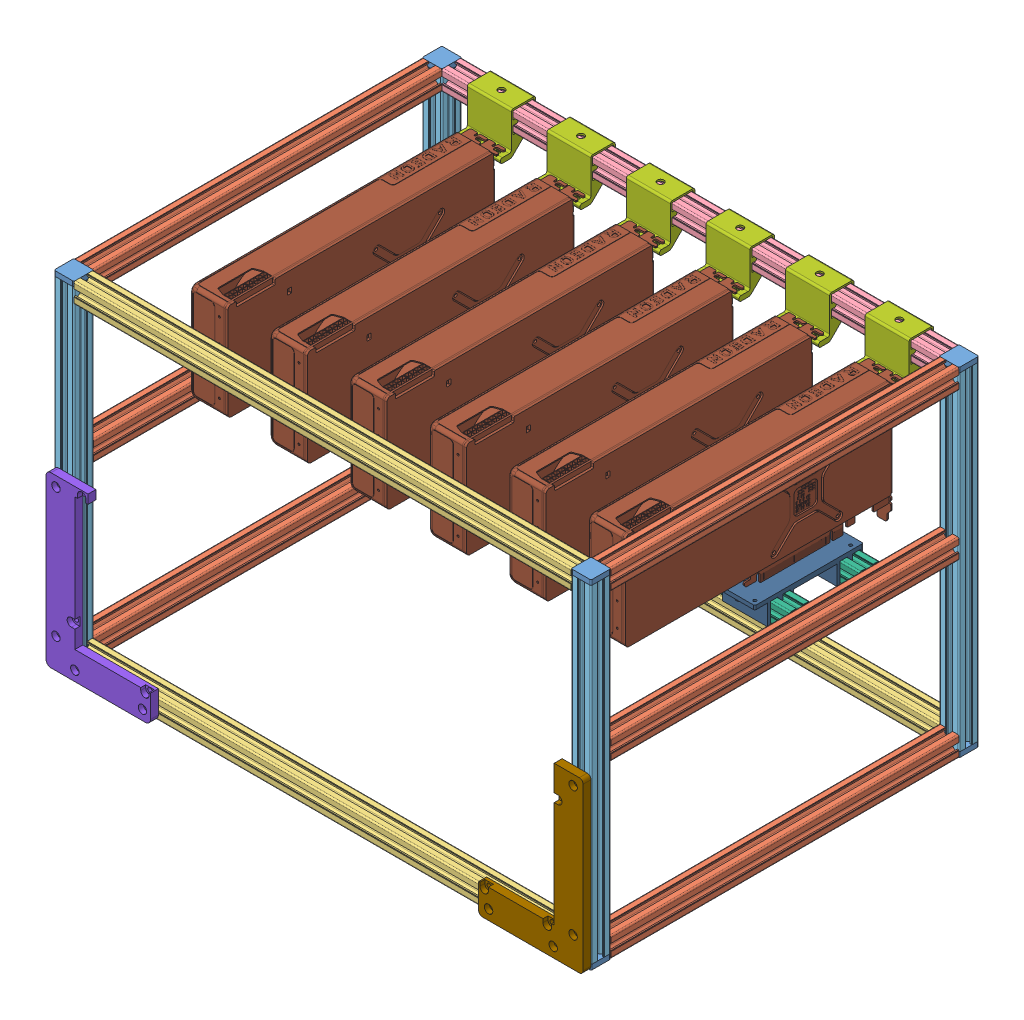
SolidWorks assembly Assem1, configuration Default. Lengths in mm.
Overall size (540 341.75 400.25).
50 component instances, 13 part files, 93 mates.
Components (placement in the parent):
- corner_joint-1: corner_joint [Default] at origin size (20 5 20)
- corner_joint-2: corner_joint [Default] at (520 335 -370) size (20 5 20)
- corner_joint-3: corner_joint [Default] at (520 335 0) size (20 5 20)
- corner_joint-4: corner_joint [Default] at (0 335 0) size (20 5 20)
- corner_joint-5: corner_joint [Default] at (0 335 -370) size (20 5 20)
- corner_joint-6: corner_joint [Default] at (520 0 0) size (20 5 20)
- corner_joint-7: corner_joint [Default] at (0 0 -370) size (20 5 20)
- corner_joint-8: corner_joint [Default] at (520 0 -370) size (20 5 20)
- AlumuniumProfile35-1: AlumuniumProfile35 [Default] at (0 182 -10) x (1 0 0) z (0 1 0) size (20 350 20)
- AlumuniumProfile35-2: AlumuniumProfile35 [Default] at (0 10 -360) x (1 0 0) z (0 -1 0) size (20 350 20)
- AlumuniumProfile35-3: AlumuniumProfile35 [Default] at (520 10 -10) x (1 0 0) z (0 1 0) size (20 350 20)
- AlumuniumProfile35-4: AlumuniumProfile35 [Default] at (0 330 -10) x (1 0 0) z (0 1 0) size (20 350 20)
- AlumuniumProfile35-5: AlumuniumProfile35 [Default] at (520 330 -10) x (1 0 0) z (0 1 0) size (20 350 20)
- AlumuniumProfile35-6: AlumuniumProfile35 [Default] at (520 182 -10) x (1 0 0) z (0 1 0) size (20 350 20)
- AlumuniumProfile35-7: AlumuniumProfile35 [Default] at (385.6516 -131.4751 125.2315) size (20 350 20) (hidden)
- AlumuniumProfile35-8: AlumuniumProfile35 [Default] at (633.6839 -115.6045 218.3051) size (20 350 20) (hidden)
- AlumuniumProfile35-9: AlumuniumProfile35 [Default] at (604.1368 -238.7208 188.5621) size (20 350 20) (hidden)
- AlumuniumProfile50-1: AlumuniumProfile50 [Default] at (10 330 0) x (0 -1 0) z (0 0 1) size (20 500 20)
- AlumuniumProfile50GPUBracket-1: AlumuniumProfile50GPUBracket [Default] at (510 330 -370) x (0 0 1) z (0 -1 0) size (20 500 20)
- AlumuniumProfile50-3: AlumuniumProfile50 [Default] at (510 10 -370) x (0 1 0) z (0 0 1) size (20 500 20)
- AlumuniumProfile33-5: AlumuniumProfile33 [Default] at (520 5 0) x (-1 0 0) z (0 0 -1) size (20 330 20)
- AlumuniumProfile33-6: AlumuniumProfile33 [Default] at (0 5 -370) size (20 330 20)
- AlumuniumProfile33-7: AlumuniumProfile33 [Default] at (0 5 0) size (20 330 20)
- AlumuniumProfile33-8: AlumuniumProfile33 [Default] at (520 5 -370) x (-1 0 0) z (0 0 -1) size (20 330 20)
- AlumuniumProfile50-5: AlumuniumProfile50 [Default] at (510 10 0) x (0 1 0) z (0 0 1) size (20 500 20)
- AlumuniumProfile50RiserBracket-4: AlumuniumProfile50RiserBracket [Default] at (510 182 -290) x (0 1 0) z (0 0 1) size (20 500 20)
- AlumuniumProfile50RiserBracket-1: AlumuniumProfile50RiserBracket [Default] at (10 182 -220) x (0 -1 0) z (0 0 1) size (20 500 20)
- GPURailBracket-5: GPURailBracket [Default] at (460.015 329.5 -370) x (1 0 0) z (0 1 0) size (44.23 35.5 42.25)
- PSUBracketRight-1: PSUBracketRight [Default] at (42.5 85 14) x (1 0 0) z (0 1 0) size (105 8 170)
- PSUBracketLeft-1: PSUBracketLeft [Default] at (477.5 85 14) x (1 0 0) z (0 1 0) size (105 8 170)
- RiserRail-1: RiserRail [Default] at (468.25 196 -248.5) x (-1 0 0) z (0 0 -1) size (45 24.5 109)
- vega 56 reference v2 v1.step-1: vega 56 reference v2 v1.step [Default] at (474.13 309.081 -356.75) x (0 0 1) z (0 -1 0) size (280 39 123.43)
- RiserRail-12: RiserRail [Default] at (388.25 196 -248.5) x (-1 0 0) z (0 0 -1) size (45 24.5 109)
- RiserRail-13: RiserRail [Default] at (308.25 196 -248.5) x (-1 0 0) z (0 0 -1) size (45 24.5 109)
- RiserRail-14: RiserRail [Default] at (228.25 196 -248.5) x (-1 0 0) z (0 0 -1) size (45 24.5 109)
- RiserRail-15: RiserRail [Default] at (148.25 196 -248.5) x (-1 0 0) z (0 0 -1) size (45 24.5 109)
- RiserRail-16: RiserRail [Default] at (68.25 196 -248.5) x (-1 0 0) z (0 0 -1) size (45 24.5 109)
- GPURailBracket-7: GPURailBracket [Default] at (380.015 329.5 -370) x (1 0 0) z (0 1 0) size (44.23 35.5 42.25)
- GPURailBracket-8: GPURailBracket [Default] at (300.015 329.5 -370) x (1 0 0) z (0 1 0) size (44.23 35.5 42.25)
- GPURailBracket-9: GPURailBracket [Default] at (220.015 329.5 -370) x (1 0 0) z (0 1 0) size (44.23 35.5 42.25)
- GPURailBracket-10: GPURailBracket [Default] at (140.015 329.5 -370) x (1 0 0) z (0 1 0) size (44.23 35.5 42.25)
- GPURailBracket-11: GPURailBracket [Default] at (60.015 329.5 -370) x (1 0 0) z (0 1 0) size (44.23 35.5 42.25)
- vega 56 reference v2 v1.step-7: vega 56 reference v2 v1.step [Default] at (394.13 309.081 -356.75) x (0 0 1) z (0 -1 0) size (280 39 123.43)
- vega 56 reference v2 v1.step-8: vega 56 reference v2 v1.step [Default] at (314.13 309.081 -356.75) x (0 0 1) z (0 -1 0) size (280 39 123.43)
- vega 56 reference v2 v1.step-9: vega 56 reference v2 v1.step [Default] at (234.13 309.081 -356.75) x (0 0 1) z (0 -1 0) size (280 39 123.43)
- vega 56 reference v2 v1.step-10: vega 56 reference v2 v1.step [Default] at (154.13 309.081 -356.75) x (0 0 1) z (0 -1 0) size (280 39 123.43)
- vega 56 reference v2 v1.step-11: vega 56 reference v2 v1.step [Default] at (74.13 309.081 -356.75) x (0 0 1) z (0 -1 0) size (280 39 123.43)
- GPUDrillingHelperExtender-1: GPUDrillingHelperExtender [Default] at (70 329.75 -370) x (0 0 -1) z (0 -1 0) size (26.5 80 23.5) (hidden)
- GPUDrillingHelperInit-1: GPUDrillingHelperInit [Default] at (10 329.75 -370) x (0 0 -1) z (0 -1 0) size (26.5 63 23.5) (hidden)
- GPUDrillingHelperExtender-2: GPUDrillingHelperExtender [Default] at (150 329.75 -370) x (0 0 -1) z (0 -1 0) size (26.5 80 23.5) (hidden)
Mates (geometry in assembly coordinates):
- Coincident36: coincident anti-aligned: plane of AlumuniumProfile33-7 through (0 5 0) normal (0 -1 0); plane of corner_joint-1 through (-8.5 5 -8.5) normal (0 1 0)
- Coincident37: coincident aligned: plane of AlumuniumProfile33-7 through (10 335 0) normal (1 0 0); plane of corner_joint-1 through (10 5 8.5) normal (1 0 0)
- Coincident38: coincident aligned: plane of AlumuniumProfile33-7 through (0 335 10) normal (0 0 1); plane of corner_joint-1 through (-8.5 5 10) normal (0 0 1)
- Coincident39: coincident anti-aligned: plane of AlumuniumProfile35-2 through (0 10 -10) normal (0 0 1); plane of corner_joint-1 through (-8.5 5 -10) normal (0 0 -1)
- Coincident40: coincident aligned: plane of AlumuniumProfile35-2 through (10 10 -10) normal (1 0 0); plane of corner_joint-1 through (10 5 8.5) normal (1 0 0)
- Coincident41: coincident aligned: plane of AlumuniumProfile35-2 through (0 0 -10) normal (0 -1 0); plane of corner_joint-1 through (-8.5 0 -8.5) normal (0 -1 0)
- Coincident42: coincident anti-aligned: plane of AlumuniumProfile50-5 through (10 10 0) normal (-1 0 0); plane of corner_joint-1 through (10 5 8.5) normal (1 0 0)
- Coincident43: coincident aligned: plane of AlumuniumProfile50-5 through (10 10 10) normal (0 0 1); plane of corner_joint-1 through (-8.5 5 10) normal (0 0 1)
- Coincident44: coincident aligned: plane of AlumuniumProfile50-5 through (10 0 0) normal (0 -1 0); plane of corner_joint-1 through (-8.5 0 -8.5) normal (0 -1 0)
- Coincident45: coincident aligned: plane of AlumuniumProfile33-5 through (520 335 0) normal (0 1 0); plane of AlumuniumProfile33-7 through (0 335 0) normal (0 1 0)
- Coincident46: coincident anti-aligned: plane of AlumuniumProfile33-5 through (510 335 0) normal (-1 0 0); plane of AlumuniumProfile50-5 through (510 10 0) normal (1 0 0)
- Coincident47: coincident aligned: plane of AlumuniumProfile33-5 through (520 335 10) normal (0 0 1); plane of AlumuniumProfile50-5 through (10 10 10) normal (0 0 1)
- Coincident48: coincident aligned: plane of AlumuniumProfile33-6 through (0 335 -370) normal (0 1 0); plane of AlumuniumProfile33-7 through (0 335 0) normal (0 1 0)
- Coincident49: coincident anti-aligned: plane of AlumuniumProfile35-2 through (0 10 -360) normal (0 0 -1); plane of AlumuniumProfile33-6 through (0 335 -360) normal (0 0 1)
- Coincident50: coincident aligned: plane of AlumuniumProfile35-2 through (-10 10 -10) normal (-1 0 0); plane of AlumuniumProfile33-6 through (-10 335 -370) normal (-1 0 0)
- Coincident51: coincident aligned: plane of AlumuniumProfile33-7 through (0 335 0) normal (0 1 0); plane of AlumuniumProfile33-8 through (520 335 -370) normal (0 1 0)
- Coincident52: coincident anti-aligned: plane of AlumuniumProfile33-8 through (510 335 -370) normal (-1 0 0); plane of AlumuniumProfile50-5 through (510 10 0) normal (1 0 0)
- Coincident53: coincident anti-aligned: plane of AlumuniumProfile35-2 through (0 10 -360) normal (0 0 -1); plane of AlumuniumProfile33-8 through (520 335 -360) normal (0 0 1)
- Coincident54: coincident anti-aligned: plane of AlumuniumProfile50-3 through (10 10 -370) normal (-1 0 0); plane of AlumuniumProfile33-6 through (10 335 -370) normal (1 0 0)
- Coincident55: coincident aligned: plane of AlumuniumProfile50-3 through (10 10 -360) normal (0 0 1); plane of AlumuniumProfile33-6 through (0 335 -360) normal (0 0 1)
- Coincident56: coincident aligned: plane of AlumuniumProfile35-2 through (0 0 -10) normal (0 -1 0); plane of AlumuniumProfile50-3 through (10 0 -370) normal (0 -1 0)
- Coincident57: coincident anti-aligned: plane of AlumuniumProfile50GPUBracket-1 through (10 330 -370) normal (-1 0 0); plane of AlumuniumProfile33-6 through (10 335 -370) normal (1 0 0)
- Coincident59: coincident anti-aligned: plane of AlumuniumProfile33-6 through (0 335 -370) normal (0 1 0); plane of corner_joint-5 through (-8.5 335 -378.5) normal (0 -1 0)
- Coincident60: coincident aligned: plane of AlumuniumProfile33-6 through (-10 335 -370) normal (-1 0 0); plane of corner_joint-5 through (-10 340 -361.5) normal (-1 0 0)
- Coincident61: coincident aligned: plane of AlumuniumProfile33-6 through (0 335 -360) normal (0 0 1); plane of corner_joint-5 through (-8.5 340 -360) normal (0 0 1)
- Coincident63: coincident anti-aligned: plane of AlumuniumProfile50-1 through (510 330 0) normal (1 0 0); plane of AlumuniumProfile33-5 through (510 335 0) normal (-1 0 0)
- Coincident64: coincident aligned: plane of AlumuniumProfile50-1 through (510 330 10) normal (0 0 1); plane of AlumuniumProfile33-5 through (520 335 10) normal (0 0 1)
- Coincident66: coincident anti-aligned: plane of AlumuniumProfile35-4 through (0 330 -360) normal (0 0 -1); plane of AlumuniumProfile33-6 through (0 335 -360) normal (0 0 1)
- Coincident67: coincident aligned: plane of AlumuniumProfile35-4 through (0 340 -360) normal (0 1 0); plane of corner_joint-5 through (-8.5 340 -378.5) normal (0 1 0)
- Coincident68: coincident aligned: plane of AlumuniumProfile35-4 through (-10 330 -360) normal (-1 0 0); plane of AlumuniumProfile33-6 through (-10 335 -370) normal (-1 0 0)
- Coincident69: coincident anti-aligned: plane of AlumuniumProfile33-8 through (520 335 -360) normal (0 0 1); plane of AlumuniumProfile35-5 through (520 330 -360) normal (0 0 -1)
- Coincident70: coincident aligned: plane of AlumuniumProfile33-8 through (510 335 -370) normal (-1 0 0); plane of AlumuniumProfile35-5 through (510 330 -360) normal (-1 0 0)
- Coincident72: coincident anti-aligned: plane of AlumuniumProfile35-3 through (520 10 -360) normal (0 0 -1); plane of AlumuniumProfile33-8 through (520 335 -360) normal (0 0 1)
- Coincident73: coincident aligned: plane of AlumuniumProfile35-3 through (510 10 -360) normal (-1 0 0); plane of AlumuniumProfile33-8 through (510 335 -370) normal (-1 0 0)
- Coincident74: coincident aligned: plane of AlumuniumProfile35-3 through (520 0 -360) normal (0 -1 0); plane of AlumuniumProfile50-3 through (10 0 -370) normal (0 -1 0)
- Coincident75: coincident aligned: plane of AlumuniumProfile33-7 through (-10 335 0) normal (-1 0 0); plane of corner_joint-4 through (-10 340 8.5) normal (-1 0 0)
- Coincident76: coincident aligned: plane of AlumuniumProfile33-7 through (0 335 10) normal (0 0 1); plane of corner_joint-4 through (-8.5 340 10) normal (0 0 1)
- Coincident77: coincident anti-aligned: plane of AlumuniumProfile33-7 through (0 335 0) normal (0 1 0); plane of corner_joint-4 through (-8.5 335 -8.5) normal (0 -1 0)
- Coincident78: coincident aligned: plane of AlumuniumProfile33-8 through (520 335 -360) normal (0 0 1); plane of corner_joint-2 through (511.5 340 -360) normal (0 0 1)
- Coincident79: coincident aligned: plane of AlumuniumProfile33-8 through (510 335 -370) normal (-1 0 0); plane of corner_joint-2 through (510 340 -361.5) normal (-1 0 0)
- Coincident80: coincident anti-aligned: plane of AlumuniumProfile33-8 through (520 335 -370) normal (0 1 0); plane of corner_joint-2 through (511.5 335 -378.5) normal (0 -1 0)
- Coincident81: coincident aligned: plane of AlumuniumProfile33-5 through (520 335 10) normal (0 0 1); plane of corner_joint-3 through (511.5 340 10) normal (0 0 1)
- Coincident82: coincident aligned: plane of AlumuniumProfile33-5 through (510 335 0) normal (-1 0 0); plane of corner_joint-3 through (510 340 8.5) normal (-1 0 0)
- Coincident83: coincident anti-aligned: plane of AlumuniumProfile33-5 through (520 335 0) normal (0 1 0); plane of corner_joint-3 through (511.5 335 -8.5) normal (0 -1 0)
- Coincident85: coincident aligned: plane of AlumuniumProfile50-5 through (10 10 10) normal (0 0 1); plane of corner_joint-6 through (511.5 5 10) normal (0 0 1)
- Coincident86: coincident aligned: plane of AlumuniumProfile33-5 through (510 335 0) normal (-1 0 0); plane of corner_joint-6 through (510 5 8.5) normal (-1 0 0)
- Coincident87: coincident aligned: plane of AlumuniumProfile50-5 through (10 0 0) normal (0 -1 0); plane of corner_joint-6 through (511.5 0 -8.5) normal (0 -1 0)
- Coincident88: coincident aligned: plane of AlumuniumProfile33-8 through (520 335 -360) normal (0 0 1); plane of corner_joint-8 through (511.5 5 -360) normal (0 0 1)
- Coincident92: coincident aligned: plane of AlumuniumProfile35-3 through (520 0 -360) normal (0 -1 0); plane of corner_joint-8 through (511.5 0 -378.5) normal (0 -1 0)
- Coincident93: coincident aligned: plane of AlumuniumProfile33-8 through (530 335 -370) normal (1 0 0); plane of corner_joint-8 through (530 5 -361.5) normal (1 0 0)
- Coincident94: coincident aligned: plane of AlumuniumProfile33-6 through (0 335 -380) normal (0 0 -1); plane of corner_joint-7 through (-8.5 5 -380) normal (0 0 -1)
- Coincident95: coincident aligned: plane of AlumuniumProfile50-3 through (10 0 -370) normal (0 -1 0); plane of corner_joint-7 through (-8.5 0 -378.5) normal (0 -1 0)
- Coincident96: coincident aligned: plane of AlumuniumProfile33-6 through (-10 335 -370) normal (-1 0 0); plane of corner_joint-7 through (-10 5 -361.5) normal (-1 0 0)
- Coincident100: coincident anti-aligned: plane of AlumuniumProfile35-1 through (0 182 -360) normal (0 0 -1); plane of AlumuniumProfile33-6 through (0 335 -360) normal (0 0 1)
- Coincident101: coincident aligned: plane of AlumuniumProfile35-1 through (-10 182 -360) normal (-1 0 0); plane of AlumuniumProfile33-6 through (-10 335 -370) normal (-1 0 0)
- Distance3: distance = 148 mm aligned: plane of AlumuniumProfile35-1 through (0 192 -360) normal (0 1 0); plane of corner_joint-5 through (-8.5 340 -378.5) normal (0 1 0)
- Coincident103: coincident anti-aligned: plane of AlumuniumProfile33-8 through (520 335 -360) normal (0 0 1); plane of AlumuniumProfile35-6 through (520 182 -360) normal (0 0 -1)
- Coincident104: coincident aligned: plane of AlumuniumProfile33-8 through (510 335 -370) normal (-1 0 0); plane of AlumuniumProfile35-6 through (510 182 -360) normal (-1 0 0)
- Coincident105: coincident aligned: plane of AlumuniumProfile35-1 through (0 192 -360) normal (0 1 0); plane of AlumuniumProfile35-6 through (520 192 -360) normal (0 1 0)
- Coincident106: coincident anti-aligned: plane of AlumuniumProfile50-4 through (510 182 -290) normal (1 0 0); plane of AlumuniumProfile35-6 through (510 182 -360) normal (-1 0 0)
- Coincident109: coincident anti-aligned: plane of AlumuniumProfile50-6 through (510 181.8711 -220) normal (1 0 0); plane of AlumuniumProfile35-6 through (510 182 -360) normal (-1 0 0)
- Coincident130: coincident anti-aligned: plane of AlumuniumProfile33-7 through (0 335 10) normal (0 0 1); plane of PSUBracketRight-1 through (42.5 85 10) normal (0 0 -1)
- Coincident131: coincident aligned: plane of AlumuniumProfile33-7 through (-10 335 0) normal (-1 0 0); plane of PSUBracketRight-1 through (-10 85 18) normal (-1 0 0)
- Coincident132: coincident aligned: plane of AlumuniumProfile50-5 through (10 0 0) normal (0 -1 0); plane of PSUBracketRight-1 through (42.5 0 18) normal (0 -1 0)
- Coincident133: coincident anti-aligned: plane of AlumuniumProfile33-5 through (520 335 10) normal (0 0 1); plane of PSUBracketLeft-1 through (477.5 85 10) normal (0 0 -1)
- Coincident134: coincident aligned: plane of AlumuniumProfile33-5 through (530 335 0) normal (1 0 0); plane of PSUBracketLeft-1 through (530 85 18) normal (1 0 0)
- Coincident135: coincident aligned: plane of AlumuniumProfile50-5 through (10 0 0) normal (0 -1 0); plane of PSUBracketLeft-1 through (477.5 0 18) normal (0 -1 0)
- Coincident150: coincident aligned: plane of AlumuniumProfile50GPUBracket-1 through (10 340 -370) normal (0 1 0); plane of corner_joint-2 through (511.5 340 -378.5) normal (0 1 0)
- Coincident151: coincident aligned: plane of AlumuniumProfile50GPUBracket-1 through (10 330 -380) normal (0 0 -1); plane of AlumuniumProfile33-8 through (520 335 -380) normal (0 0 -1)
- Coincident152: coincident aligned: plane of AlumuniumProfile35-5 through (520 340 -360) normal (0 1 0); plane of AlumuniumProfile50GPUBracket-1 through (10 340 -370) normal (0 1 0)
- Coincident153: coincident aligned: plane of AlumuniumProfile50-1 through (510 340 0) normal (0 1 0); plane of AlumuniumProfile50GPUBracket-1 through (10 340 -370) normal (0 1 0)
- Distance15: distance = 0.5 mm anti-aligned: plane of RiserRail-1 through (468.25 171.5 -209.5) normal (0 0 -1); plane of AlumuniumProfile50-6 through (510 182 -210) normal (0 0 1)
- Distance16: distance = 19.25 mm anti-aligned: plane of RiserRail-1 through (490.75 192 -301.5) normal (1 0 0); plane of AlumuniumProfile35-6 through (510 182 -360) normal (-1 0 0)
- Distance20: distance = 0.5 mm anti-aligned: plane of GPURailBracket-5 through (437.9 329.5 -359.5) normal (0 0 -1); plane of AlumuniumProfile50GPUBracket-1 through (10 330 -360) normal (0 0 1)
- Coincident174: coincident anti-aligned: plane of AlumuniumProfile50GPUBracket-1 through (10 340 -370) normal (0 1 0); plane of GPURailBracket-5 through (437.9 340 -370) normal (0 -1 0)
- Distance21: distance = 27.87 mm anti-aligned: plane of GPURailBracket-5 through (482.13 329.5 -370) normal (1 0 0); plane of corner_joint-2 through (510 340 -361.5) normal (-1 0 0)
- Concentric9: concentric anti-aligned: cylinder of GPURailBracket-5 through (454.63 297.5 -352.25) axis (0 1 0) radius 1.5; cylinder of vega 56 reference v2 v1.step-1 through (454.63 306 -352.25) axis (0 -1 0) radius 1.5
- Coincident176: coincident anti-aligned: plane of GPURailBracket-5 through (437.9 304.5 -370) normal (0 1 0); plane of vega 56 reference v2 v1.step-1 through (474.13 304.5 -345.25) normal (0 -1 0)
- Parallel15: parallel anti-aligned: plane of GPURailBracket-5 through (437.9 329.5 -357.75) normal (0 0 1); plane of vega 56 reference v2 v1.step-1 through (474.13 185.2588 -345.25) normal (0 0 -1)
- Coincident178: coincident aligned: plane of AlumuniumProfile35-1 through (0 192 -360) normal (0 1 0); plane of AlumuniumProfile50RiserBracket-4 through (10 192 -290) normal (0 1 0)
- Distance22: distance = 60 mm anti-aligned: plane of AlumuniumProfile50RiserBracket-4 through (10 182 -300) normal (0 0 -1); plane of AlumuniumProfile33-6 through (0 335 -360) normal (0 0 1)
- Distance23: distance = 70 mm aligned: plane of AlumuniumProfile50RiserBracket-4 through (10 182 -280) normal (0 0 1); plane of AlumuniumProfile50RiserBracket-1 through (510 182 -210) normal (0 0 1)
- Coincident181: coincident anti-aligned: plane of AlumuniumProfile50RiserBracket-4 through (10 192 -290) normal (0 1 0); plane of RiserRail-1 through (447.25 192 -195.5) normal (0 -1 0)
- Coincident182: coincident aligned: plane of AlumuniumProfile50RiserBracket-4 through (10 192 -290) normal (0 1 0); plane of AlumuniumProfile50RiserBracket-1 through (510 192 -220) normal (0 1 0)
- Concentric10: concentric: cylinder of AlumuniumProfile50GPUBracket-1 through (60 317.7147 -370) axis (0 1 0) radius 3; cylinder of GPUDrillingHelperInit-1 through (60 311.0147 -370) axis (0 1 0) radius 3
- Coincident183: coincident: plane of AlumuniumProfile50GPUBracket-1 through (10 330 -370) normal (-1 0 0); plane of GPUDrillingHelperInit-1 through (10 329.75 -370) normal (1 0 0)
- Coincident184: coincident anti-aligned: plane of AlumuniumProfile50GPUBracket-1 through (10 340 -370) normal (0 1 0); plane of GPUDrillingHelperInit-1 through (70 340 -370) normal (0 -1 0)
- Concentric11: concentric: cylinder of AlumuniumProfile50GPUBracket-1 through (140 317.7147 -370) axis (0 1 0) radius 3; cylinder of GPUDrillingHelperExtender-1 through (140 317 -370) axis (0 1 0) radius 3
- Coincident185: coincident: plane of GPUDrillingHelperExtender-1 through (70 329.75 -370) normal (-1 0 0); plane of GPUDrillingHelperInit-1 through (70 329.75 -370) normal (1 0 0)
- Coincident186: coincident anti-aligned: plane of AlumuniumProfile50GPUBracket-1 through (10 340 -370) normal (0 1 0); plane of GPUDrillingHelperExtender-1 through (150 340 -370) normal (0 -1 0)
- Concentric12: concentric: cylinder of AlumuniumProfile50GPUBracket-1 through (220 317.7147 -370) axis (0 1 0) radius 3; cylinder of GPUDrillingHelperExtender-2 through (220 317 -370) axis (0 1 0) radius 3
- Coincident187: coincident: plane of GPUDrillingHelperExtender-1 through (150 329.75 -370) normal (1 0 0); plane of GPUDrillingHelperExtender-2 through (150 329.75 -370) normal (-1 0 0)
- Coincident188: coincident anti-aligned: plane of AlumuniumProfile50GPUBracket-1 through (10 340 -370) normal (0 1 0); plane of GPUDrillingHelperExtender-2 through (230 340 -370) normal (0 -1 0)
